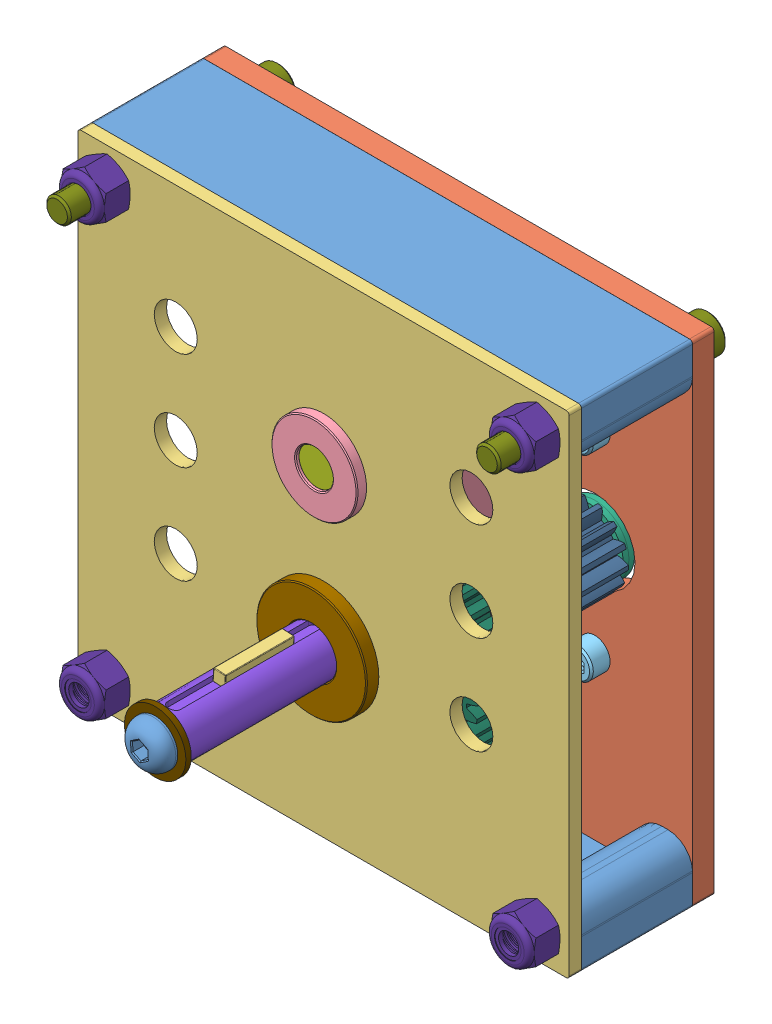
SolidWorks assembly toughbox, configuration Default. Lengths in mm.
Overall size (127.03 127 97.81).
37 component instances, 21 part files, 0 mates.
Components (placement in the parent):
- am-2650 TB Spacer-1: am-2650 TB Spacer [Default] at (-20.7449 79.3887 80.3249) size (127 14.35 28.75)
- am-0155 Toughbox Motor Plate-1: am-0155 Toughbox Motor Plate [Default] at (21.1445 38.6364 74.7369) x (1 0 0) z (0 1 0) size (127 5.59 127)
- am-2650 TB Spacer-2: am-2650 TB Spacer [Default] at (90.4055 -31.7363 80.3249) x (-1 0 0) z (0 0 1) size (127 14.35 28.75)
- Toughbox d02 am-0261-1: Toughbox d02 am-0261 [Default] at (21.1699 38.6364 109.0777) x (1 0 0) z (0 1 0) size (127 3.17 127)
- FR6ZZ Bearing-1: FR6ZZ Bearing [Default] at (40.6889 12.4563 81.8489) x (0.923728 0.383049 0) z (0 0 -1) size (24.69 24.69 7.16)
- FR6ZZ Bearing-2: FR6ZZ Bearing [Default] at (40.6889 53.1471 81.8489) x (0.923728 0.383049 0) z (0 0 -1) size (24.69 24.69 7.16)
- 10-32x0500_shcs_HX-SHCS 0.19-32x1.375x1-C-1: 10-32x0500_shcs_HX-SHCS 0.19-32x1.375x1-C [Default] at (-3.3906 4.7762 85.1509) x (0 0 -1) z (1 0 0) size (17.53 7.94 7.94)
- 10-32x0500_shcs_HX-SHCS 0.19-32x1.375x1-C-2: 10-32x0500_shcs_HX-SHCS 0.19-32x1.375x1-C [Default] at (-3.3906 55.5762 85.1509) x (0 0 -1) z (1 0 0) size (17.53 7.94 7.94)
- 10-32x0500_shcs_HX-SHCS 0.19-32x1.375x1-C-3: 10-32x0500_shcs_HX-SHCS 0.19-32x1.375x1-C [Default] at (73.0258 55.5762 85.1509) x (0 0 -1) z (1 0 0) size (17.53 7.94 7.94)
- 10-32x0500_shcs_HX-SHCS 0.19-32x1.375x1-C-4: 10-32x0500_shcs_HX-SHCS 0.19-32x1.375x1-C [Default] at (73.0258 4.7762 85.1509) x (0 0 -1) z (1 0 0) size (17.53 7.94 7.94)
- 5-16 washer-1: 5-16 washer [Default] at (-3.3906 30.1762 78.8009) size (17.53 17.53 1.47)
- 5-16 washer-2: 5-16 washer [Default] at (-3.3906 30.1762 80.2741) size (17.53 17.53 1.47)
- 5-16 washer-3: 5-16 washer [Default] at (73.0258 30.1762 78.8009) size (17.53 17.53 1.47)
- 5-16 washer-4: 5-16 washer [Default] at (73.0258 30.1762 80.2741) size (17.53 17.53 1.47)
- Toughbox Small Hex Shaft-1: Toughbox Small Hex Shaft [Default] at (34.8176 44.1716 75.8037) x (0.5 -0.866025 0) z (0 0 1) size (11 9.53 38.11)
- TB Output Shaft-1: TB Output Shaft [Default] at (-2.2613 22.7278 107.2489) x (-0.997664 0.068316 0) z (0.068316 0.997664 0) size (14.66 92.33 12.7)
- FR6ZZ Bearing-3: FR6ZZ Bearing [Default] at (43.7045 38.1296 107.5537) size (24.69 24.69 7.16)
- FR8ZZ Bearing-1: FR8ZZ Bearing [Default] at (43.7045 -2.5612 107.5029) size (31.75 31.75 7.95)
- 14T CIM Gear-1: 14T CIM Gear [Default] at (-3.3906 30.1762 81.7473) size (20.03 20.32 12.7)
- 14T CIM Gear-2: 14T CIM Gear [Default] at (73.0258 30.1762 81.7473) x (0.98536 0.170489 0) z (0 0 1) size (20.03 20.32 12.7)
- 8mm_spring_clip am-0033-1: 8mm_spring_clip am-0033 [Default] at (-3.3906 30.1762 94.4473) x (0 0 1) z (-1 0 0) size (1.12 14.83 14.83)
- 8mm_spring_clip am-0033-2: 8mm_spring_clip am-0033 [Default] at (73.0258 30.1762 94.4473) x (0 0 1) z (-1 0 0) size (1.12 14.83 14.83)
- 500-e-klip_smart-1: 500-e-klip_smart [Default] at (62.138 11.0174 96.4031) x (1 0 0) z (0 1 0) size (19.07 1.27 20.95)
- 50T 20dp 375hex_Inch - Spur gear 20DP 50T 14.5PA .372FW ---S50N3.0H2.0L0.25N-1: 50T 20dp 375hex_Inch - Spur gear 20DP 50T 14.5PA .372FW ---S50N3.0H2.0L0.25N [Default] at (34.8176 44.1716 92.0089) x (0 0 -1) z (1 0 0) size (10.16 65.97 66.04)
- 14T 20dp 375hex_Inch - Spur gear 20DP 14T 14.5PA .568FW ---S14N3.0H2.0L0.25N-1: 14T 20dp 375hex_Inch - Spur gear 20DP 14T 14.5PA .568FW ---S14N3.0H2.0L0.25N [Default] at (34.843 44.1716 92.0089) x (0 0 1) z (-1 0 0) size (15.14 19.97 20.32)
- 50T 20dp 500hex-1: 50T 20dp 500hex [Default] at (34.8176 3.4808 96.4031) x (0.997664 -0.068316 0) z (0 0 1) size (65.97 66.04 10.62)
- SHCS 14-20 x 2-1: SHCS 14-20 x 2 [Default] at (90.3801 79.3887 68.1837) x (1 0 0) z (0 1 0) size (9.53 57.35 9.53)
- SHCS 14-20 x 2-2: SHCS 14-20 x 2 [Default] at (-20.7449 79.3887 68.1837) x (1 0 0) z (0 1 0) size (9.53 57.35 9.53)
- 14-20 Nylock Nut_97135A210-1: 14-20 Nylock Nut_97135A210 [Default] at (-20.7195 79.3887 112.2527) x (1 0 0) z (0 -1 0) size (11.11 8.13 12.83)
- 14-20 Nylock Nut_97135A210-2: 14-20 Nylock Nut_97135A210 [Default] at (-20.7195 -31.7363 112.2527) x (1 0 0) z (0 -1 0) size (11.11 8.13 12.83)
- 14-20 Nylock Nut_97135A210-3: 14-20 Nylock Nut_97135A210 [Default] at (90.4055 -31.7363 112.2527) x (1 0 0) z (0 -1 0) size (11.11 8.13 12.83)
- 14-20 Nylock Nut_97135A210-4: 14-20 Nylock Nut_97135A210 [Default] at (90.4055 79.3887 112.2527) x (1 0 0) z (0 -1 0) size (11.11 8.13 12.83)
- 0.25 Flat Washer_Preferred Wide FW 0.25-1: 0.25 Flat Washer_Preferred Wide FW 0.25 [Default] at (34.8176 3.4808 154.3659) x (0 0 -1) z (1 0 0) size (1.4 15.88 15.88)
- BHCS 14-20 x 0.5-1: BHCS 14-20 x 0.5 [Default] at (34.8176 3.4808 159.8269) x (0.554675 -0.832067 0) z (-0.832067 -0.554675 0) size (11.69 16.79 11.69)
- 2mm x 2mm x 10mm Machine Key_smart-1: 2mm x 2mm x 10mm Machine Key_smart [Default] at (-25.2074 30.9762 84.4473) x (0 0 1) z (0 -1 0) size (10 2 2)
- 2mm x 2mm x 10mm Machine Key_smart-2: 2mm x 2mm x 10mm Machine Key_smart [Default] at (79.0195 13.1317 84.4473) x (0 0 1) z (0.98536 0.170489 0) size (10 2 2)
- 125 x 124 x 700 Machine Key-1: 125 x 124 x 700 Machine Key [Default] at (33.4941 11.4893 125.5831) x (0 0 1) z (-0.997664 0.068316 0) size (17.78 3.17 3.17)
